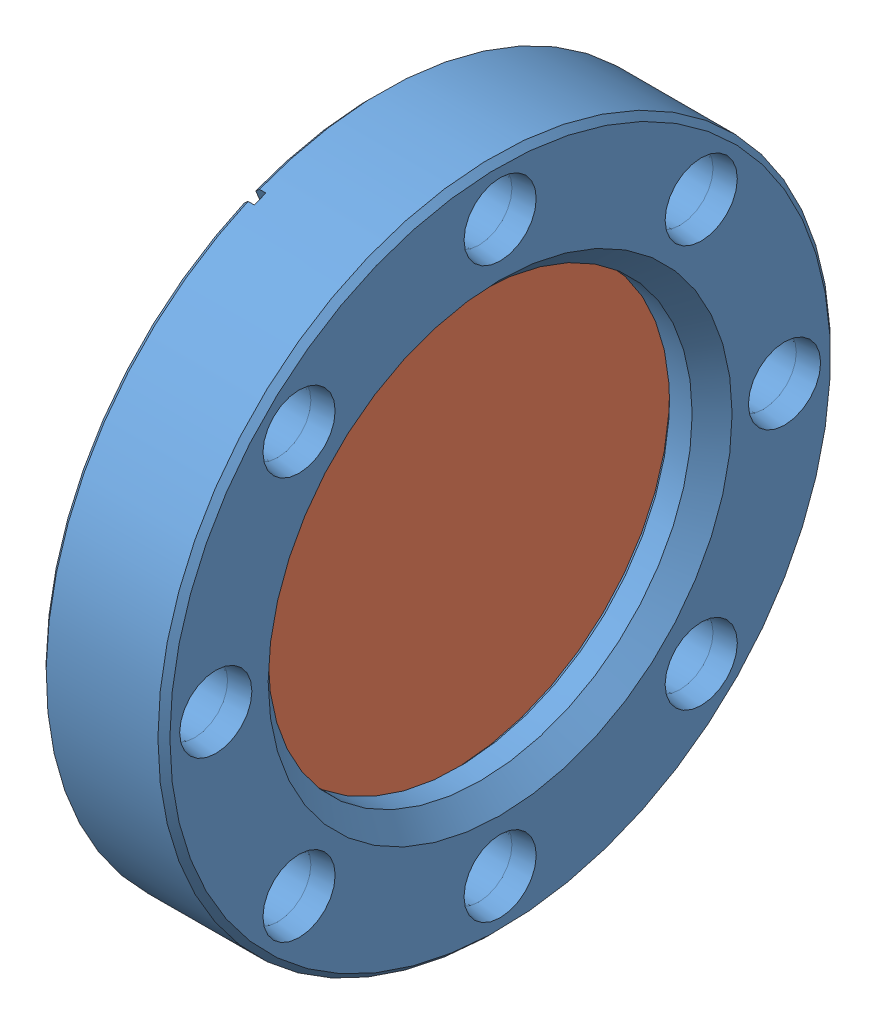
SolidWorks assembly 100015, configuration Default. Lengths in mm.
Overall size (15.76 85.6 85.6).
2 component instances, 2 part files, 2 mates.
Components (placement in the parent):
- 915003-1: 915003 [Default] at (29.751 46.3734 61.5544) size (15.76 85.6 85.6)
- 910015-1: 910015 [Default] at (30.4114 46.3734 61.5544) x (1 0 0) z (0 0.291085 0.956697) size (8.84 61.67 61.67)
Mates (geometry in assembly coordinates):
- Concentric1: concentric: cylinder of 915003-1 through (29.751 46.3734 61.5544) axis (-1 0 0) radius 42.799; cylinder of 910015-1 through (30.4114 46.3734 61.5544) axis (-1 0 0) radius 30.8356
- Coincident1: coincident anti-aligned: plane of 915003-1 through (39.3014 77.3233 61.5544) normal (-1 0 0); plane of 910015-1 through (39.3014 75.8737 52.5786) normal (1 0 0)
